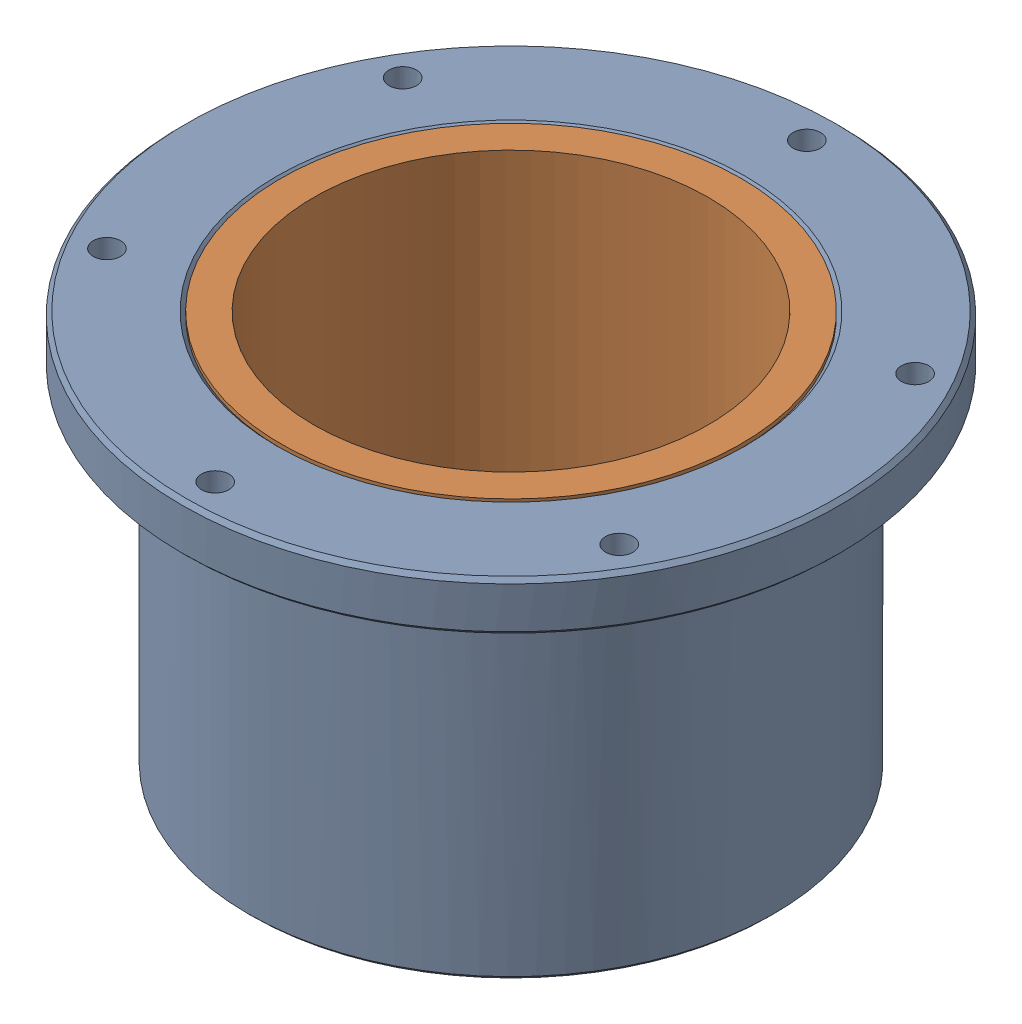
SolidWorks assembly bushing_hub_asm_1, configuration Default. Lengths in mm.
Overall size (63.5 38.1 63.5).
2 component instances, 2 part files, 0 mates.
Components (placement in the parent):
- revo2_steering_hub_1-1: revo2_steering_hub_1 [Default] at origin size (63.5 38.1 63.5)
- 1_1-1: 1_1 [Default] at (-0.595 0 0) size (44.45 38.1 44.45)
